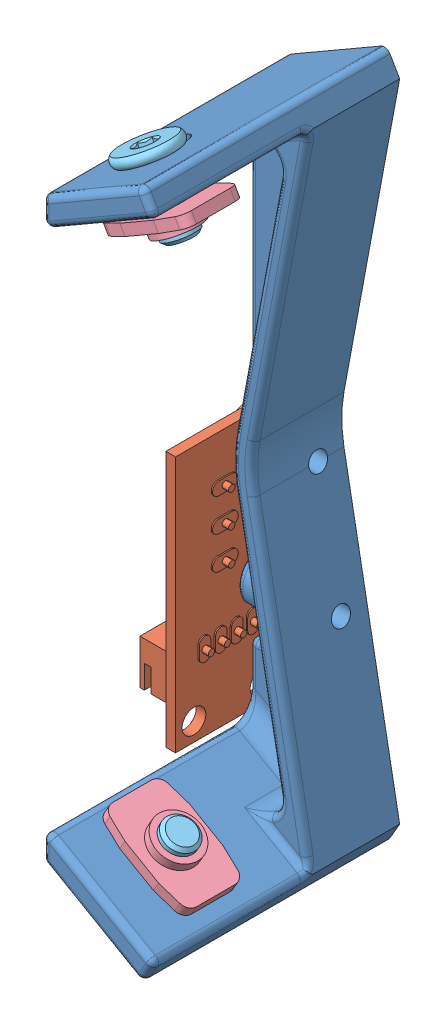
SolidWorks assembly Endstop Assembly, configuration Default. Lengths in mm.
Overall size (24.96 106.2 41.89).
8 component instances, 5 part files, 19 mates.
Components (placement in the parent):
- Minimal Endstop Mount Bridge-1: Minimal Endstop Mount Bridge [Default] at (-27.8078 -37.4107 -8.311) size (17.4 106.2 38)
- Bigtree-Tech_Endstop(Makerbot_Style)-1: Bigtree-Tech_Endstop(Makerbot_Style) [Default] at (-46.6283 -7.9557 0.964) x (0 -1 0) z (0 0 1) size (39.71 8.6 21.29)
- M3 x 0.50 mm Thread-1: M3 x 0.50 mm Thread [8mm] at (-48.2783 -10.0607 -4.311) x (0 0.741174 0.671313) z (-1 0 0) size (5.7 5.7 9.77)
- M3 x 0.50 mm Thread-2: M3 x 0.50 mm Thread [8mm] at (-48.2783 8.9393 -4.311) x (0 0.62536 0.780337) z (-1 0 0) size (5.7 5.7 9.77)
- Tee Nut-2: Tee Nut [Default] at (-35.568 -30.8519 19.689) x (0.866025 -0.5 0) z (0.5 0.866025 0) size (15 10 3)
- Low Profile Screw M5-2: Low Profile Screw M5 [M5 x 10] at (-33.468 -27.2146 19.689) x (0.5 0.866025 0) z (-0.627766 0.362441 -0.688874) size (11.62 9 9)
- Low Profile Screw M5-3: Low Profile Screw M5 [M5 x 10] at (-33.468 52.3931 19.689) x (0.5 -0.866025 0) z (0.799742 0.461731 -0.383689) size (11.62 9 9)
- Tee Nut-3: Tee Nut [Default] at (-35.568 56.0304 19.689) x (-0.866025 -0.5 0) z (0.5 -0.866025 0) size (15 10 3)
Mates (geometry in assembly coordinates):
- Concentric1: concentric aligned: cylinder of Minimal Endstop Mount Bridge-1 through (-27.8078 -10.0607 -4.311) axis (-1 0 0) radius 1.45; cylinder of Bigtree-Tech_Endstop(Makerbot_Style)-1 through (-45.1283 -10.0607 -4.311) axis (-1 0 0) radius 1.85
- Concentric2: concentric aligned: cylinder of Minimal Endstop Mount Bridge-1 through (-27.8078 8.9393 -4.311) axis (-1 0 0) radius 1.45; cylinder of Bigtree-Tech_Endstop(Makerbot_Style)-1 through (-45.1283 8.9393 -4.311) axis (-1 0 0) radius 1.85
- Coincident1: coincident anti-aligned: plane of Minimal Endstop Mount Bridge-1 through (-45.1283 -11.4107 -2.311) normal (-1 0 0); plane of Bigtree-Tech_Endstop(Makerbot_Style)-1 through (-45.1283 -7.9557 0.964) normal (1 0 0)
- Concentric3: concentric anti-aligned: cylinder of Minimal Endstop Mount Bridge-1 through (-27.8078 -10.0607 -4.311) axis (-1 0 0) radius 1.45; cylinder of M3 x 0.50 mm Thread-1 through (-38.6283 -10.0607 -4.311) axis (1 0 0) radius 1.5
- Coincident2: coincident anti-aligned: plane of Bigtree-Tech_Endstop(Makerbot_Style)-1 through (-46.6283 -7.9557 0.964) normal (-1 0 0); plane of M3 x 0.50 mm Thread-1 through (-46.6283 -11.974 -2.1986) normal (1 0 0)
- Concentric4: concentric anti-aligned: cylinder of Minimal Endstop Mount Bridge-1 through (-27.8078 8.9393 -4.311) axis (-1 0 0) radius 1.45; cylinder of M3 x 0.50 mm Thread-2 through (-38.6283 8.9393 -4.311) axis (1 0 0) radius 1.5
- Coincident3: coincident anti-aligned: plane of Bigtree-Tech_Endstop(Makerbot_Style)-1 through (-46.6283 -7.9557 0.964) normal (-1 0 0); plane of M3 x 0.50 mm Thread-2 through (-46.6283 6.7153 -2.5287) normal (1 0 0)
- Distance1: distance = 1.8 mm anti-aligned: plane of Minimal Endstop Mount Bridge-1 through (-29.8078 66.0534 -8.311) normal (-0.5 0.866025 0); plane of ? through (-34.1719 65.6122 16.689) normal (0.5 -0.866025 0)
- Parallel1: parallel aligned: plane of Minimal Endstop Mount Bridge-1 through (-29.8078 66.0534 29.689) normal (0 0 1); plane of ? through (-42.7661 62.4979 24.689) normal (0 0 1)
- Concentric5: concentric aligned: cylinder of Minimal Endstop Mount Bridge-1 through (-38.468 -35.8748 19.689) axis (0.5 0.866025 0) radius 2.6; cylinder of Low Profile Screw M5-2 through (-38.468 -35.8748 19.689) axis (0.5 0.866025 0) radius 2.5
- Coincident5: coincident anti-aligned: plane of Minimal Endstop Mount Bridge-1 through (-29.8078 -40.8748 -8.311) normal (-0.5 -0.866025 0); plane of Low Profile Screw M5-2 through (-35.9854 -37.3082 16.6725) normal (0.5 0.866025 0)
- Concentric6: concentric aligned: cylinder of Tee Nut-2 through (-34.068 -28.2538 19.689) axis (0.5 0.866025 0) radius 2.1; cylinder of Low Profile Screw M5-2 through (-38.468 -35.8748 19.689) axis (0.5 0.866025 0) radius 2.5
- Parallel2: parallel aligned: plane of Minimal Endstop Mount Bridge-1 through (-29.8078 -40.8748 29.689) normal (0 0 1); plane of Tee Nut-2 through (-37.3661 -27.9662 24.689) normal (0 0 1)
- Distance2: distance = 1.8 mm anti-aligned: plane of Minimal Endstop Mount Bridge-1 through (-27.8078 -37.4107 -8.311) normal (0.5 0.866025 0); plane of Tee Nut-2 through (-30.3719 -33.8519 16.689) normal (-0.5 -0.866025 0)
- Concentric7: concentric aligned: cylinder of Low Profile Screw M5-3 through (-38.468 61.0534 19.689) axis (0.5 -0.866025 0) radius 2.5; cylinder of Tee Nut-3 through (-34.068 53.4324 19.689) axis (0.5 -0.866025 0) radius 2.1
- Concentric8: concentric aligned: cylinder of Minimal Endstop Mount Bridge-1 through (-38.468 61.0534 19.689) axis (0.5 -0.866025 0) radius 2.6; cylinder of Low Profile Screw M5-3 through (-38.468 61.0534 19.689) axis (0.5 -0.866025 0) radius 2.5
- Coincident8: coincident anti-aligned: plane of Minimal Endstop Mount Bridge-1 through (-29.8078 66.0534 -8.311) normal (-0.5 0.866025 0); plane of Low Profile Screw M5-3 through (-39.8508 60.255 15.8461) normal (0.5 -0.866025 0)
- Parallel3: parallel aligned: plane of Minimal Endstop Mount Bridge-1 through (-29.8078 66.0534 29.689) normal (0 0 1); plane of Tee Nut-3 through (-32.17 56.1448 24.689) normal (0 0 1)
- Distance3: distance = 1.8 mm anti-aligned: plane of Minimal Endstop Mount Bridge-1 through (-27.8078 62.5893 -8.311) normal (0.5 -0.866025 0); plane of Tee Nut-3 through (-40.7642 53.0304 16.689) normal (-0.5 0.866025 0)
